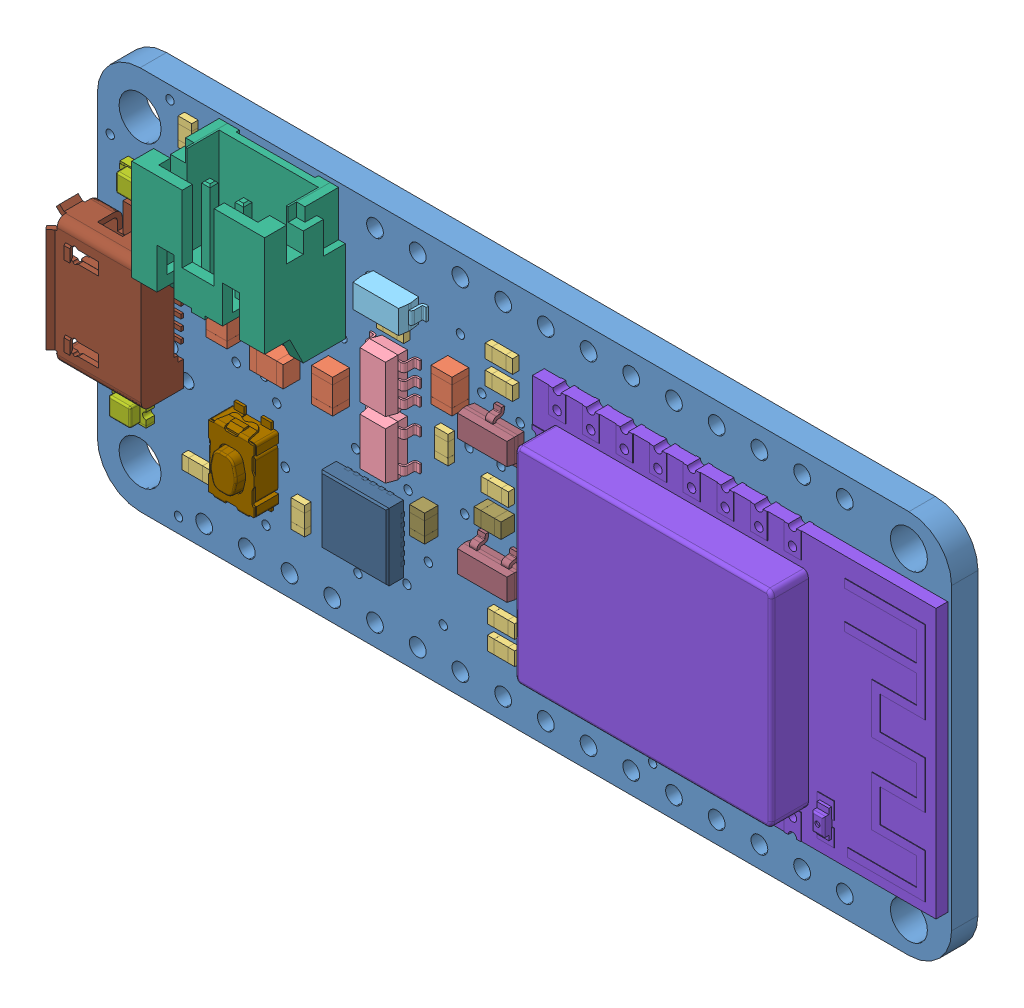
SolidWorks assembly Adafruit ESP8266 Feather, configuration Default. Lengths in mm.
Overall size (51.25 22.86 6.37).
31 component instances, 13 part files, 0 mates.
Components (placement in the parent):
- Adafruit ESP8266 Feather.step-1: Adafruit ESP8266 Feather.step [Default] at origin size (51.25 22.86 6.37)
  - PCB Component.step-1: PCB Component.step [Default] at origin size (51.25 22.86 6.37)
    - Board.step-1: Board.step [Default] at origin size (50.8 22.86 1.57)
    - 10uF.step-1: 10uF.step [Default] at (8.088 12.959 1.57) x (0 1 0) z (0 0 1) size (2 1.25 1)
    - 10uF.step-2: 10uF.step [Default] at (14.366 12.64 1.57) x (0 -1 0) z (0 0 1) size (2 1.25 1)
    - 10uF.step-3: 10uF.step [Default] at (11.049 12.192 1.57) x (-1 0 0) z (0 0 1) size (2 1.25 1)
    - 10uF.step-4: 10uF.step [Default] at (21.463 16.192 1.57) x (0 -1 0) z (0 0 1) size (2 1.25 1)
    - 10K.step-1: 10K.step [Default] at (12.302 4.775 1.57) x (0 -1 0) z (0 0 1) size (1.62 0.81 0.38)
    - 10K.step-2: 10K.step [Default] at (6.223 4.191 1.57) size (1.62 0.81 0.38)
    - 10K.step-3: 10K.step [Default] at (20.828 12.7 1.57) x (0 -1 0) z (0 0 1) size (1.62 0.81 0.38)
    - 10K.step-4: 10K.step [Default] at (24.257 18.923 1.57) x (-1 0 0) z (0 0 1) size (1.62 0.81 0.38)
    - 10K.step-5: 10K.step [Default] at (24.257 17.526 1.57) x (-1 0 0) z (0 0 1) size (1.62 0.81 0.38)
    - 10K.step-6: 10K.step [Default] at (24.384 3.937 1.57) size (1.62 0.81 0.38)
    - 10K.step-7: 10K.step [Default] at (24.384 5.334 1.57) x (-1 0 0) z (0 0 1) size (1.62 0.81 0.38)
    - 10K.step-8: 10K.step [Default] at (5.588 21.082 1.57) x (0 -1 0) z (0 0 1) size (1.62 0.81 0.38)
    - 10K.step-9: 10K.step [Default] at (24.003 11.938 1.57) x (-1 0 0) z (0 0 1) size (1.62 0.81 0.38)
    - 10K.step-10: 10K.step [Default] at (17.78 17.272 1.57) size (1.62 0.81 0.38)
    - MCP73831T-2ACI_OT.step-1: MCP73831T-2ACI_OT.step [Default] at (17.78 14.986 1.57) x (0 1 0) z (0 0 1) size (3 3 1.4)
    - MCP73831T-2ACI_OT.step-2: MCP73831T-2ACI_OT.step [Default] at (17.78 11.557 1.57) x (0 -1 0) z (0 0 1) size (3 3 1.4)
    - MBR120.step-1: MBR120.step [Default] at (17.907 18.796 1.57) x (-1 0 0) z (0 0 1) size (3.6 1.4 1.35)
    - JSTPH.step-1: JSTPH.step [Default] at (10.795 19.304 1.57) size (7.9 8.6 4.8)
    - RED.step-1: RED.step [Default] at (2.413 5.588 1.57) x (0 -1 0) z (0 0 1) size (1.25 2.02 1.1)
    - RED.step-2: RED.step [Default] at (2.858 17.336 1.57) x (0 -1 0) z (0 0 1) size (1.25 2.02 1.1)
    - ESP-12.step-1: ESP-12.step [Default] at (36.322 11.43 1.57) x (0 -1 0) z (0 0 1) size (16 24 2.95)
    - KMR2.step-1: KMR2.step [Default] at (9.398 6.35 1.57) x (0 -1 0) z (0 0 1) size (4.6 2.8 1.94)
    - CP2104.step-1: CP2104.step [Default] at (16.256 6.477 1.57) size (4 4 1)
    - 20329.step-1: 20329.step [Default] at (4.445 11.43 1.57) x (0 -1 0) z (0 0 1) size (8.8 5.6 3)
    - 1K.step-1: 1K.step [Default] at (24.003 10.541 1.57) size (1.6 0.9 0.8)
    - 1K.step-2: 1K.step [Default] at (19.812 8.382 1.57) x (0 -1 0) z (0 0 1) size (1.6 0.9 0.8)
    - mmbt2222.step-1: mmbt2222.step [Default] at (24.003 8.001 1.57) x (-1 0 0) z (0 0 1) size (3.04 2.64 1.12)
    - mmbt2222.step-2: mmbt2222.step [Default] at (24.003 14.986 1.57) size (3.04 2.64 1.12)
